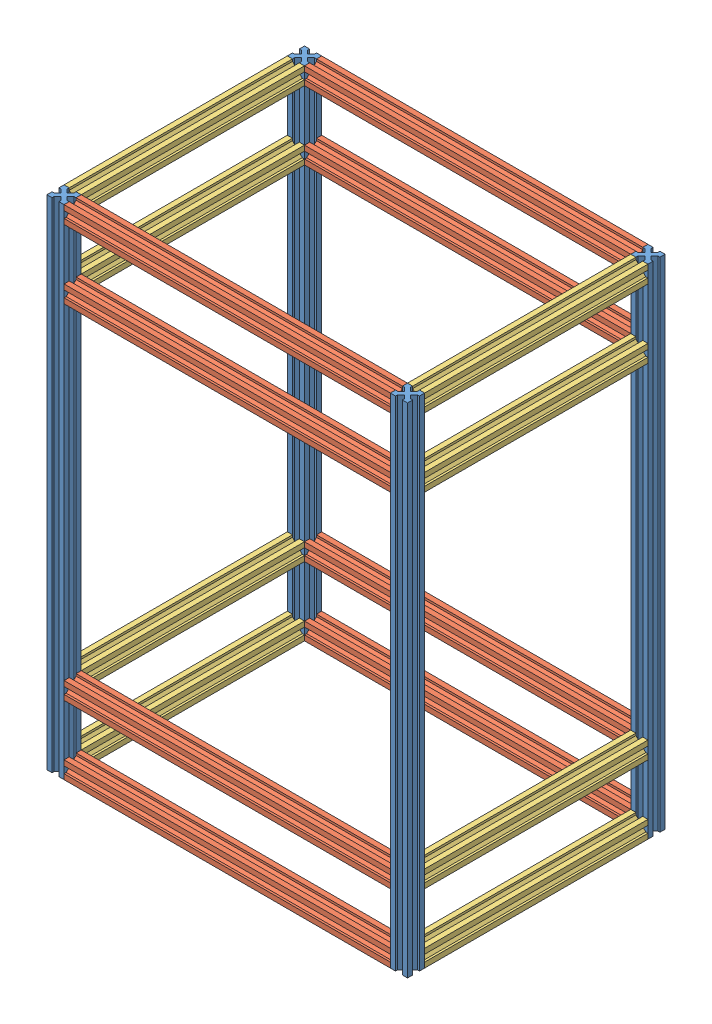
SolidWorks assembly module externe1.0, configuration Défaut. Lengths in mm.
Overall size (420 580 300).
22 component instances, 3 part files, 31 mates.
Components (placement in the parent):
- base chassis horizontale-1: base chassis horizontale [Défaut] at (107.5488 34.6411 0) size (420 580 20)
  - profilé 580-1: profilé 580 [Défaut] at (-152.6624 -292.9685 550) size (20 580 20)
  - profilé 380-1: profilé 380 [Défaut] at (-152.6624 -272.9685 550) x (0 0 1) z (0 1 0) size (20 380 20)
  - profilé 380-2: profilé 380 [Défaut] at (227.3376 -212.9685 550) x (0 0 1) z (0 -1 0) size (20 380 20)
  - profilé 380-3: profilé 380 [Défaut] at (227.3376 267.0315 550) x (0 0 1) z (0 -1 0) size (20 380 20)
  - profilé 380-4: profilé 380 [Défaut] at (227.3376 187.0315 550) x (0 0 1) z (0 -1 0) size (20 380 20)
  - profilé 580-2: profilé 580 [Défaut] at (247.3376 -292.9685 530) x (0 0 -1) z (1 0 0) size (20 580 20)
- profilé 260-1: profilé 260 [Défaut] at (-45.1136 -238.3275 550) x (0 1 0) z (1 0 0) size (20 260 20)
- profilé 260-2: profilé 260 [Défaut] at (334.8864 -258.3275 810) x (-1 0 0) z (0 -1 0) size (20 260 20)
- profilé 260-3: profilé 260 [Défaut] at (334.8864 321.6725 550) x (-1 0 0) z (0 1 0) size (20 260 20)
- profilé 260-4: profilé 260 [Défaut] at (-65.1136 321.6725 550) x (-1 0 0) z (0 1 0) size (20 260 20)
- base chassis horizontale-2: base chassis horizontale [Défaut] at (182.224 28.704 280) x (-1 0 0) z (0 0 1) size (420 580 20)
  - profilé 580-1: profilé 580 [Défaut] at (-152.6624 -292.9685 550) size (20 580 20)
  - profilé 380-1: profilé 380 [Défaut] at (-152.6624 -272.9685 550) x (0 0 1) z (0 1 0) size (20 380 20)
  - profilé 380-2: profilé 380 [Défaut] at (227.3376 -212.9685 550) x (0 0 1) z (0 -1 0) size (20 380 20)
  - profilé 380-3: profilé 380 [Défaut] at (227.3376 267.0315 550) x (0 0 1) z (0 -1 0) size (20 380 20)
  - profilé 380-4: profilé 380 [Défaut] at (227.3376 187.0315 550) x (0 0 1) z (0 -1 0) size (20 380 20)
  - profilé 580-2: profilé 580 [Défaut] at (247.3376 -292.9685 530) x (0 0 -1) z (1 0 0) size (20 580 20)
- profilé 260-5: profilé 260 [Défaut] at (-65.1136 -158.3275 550) x (-1 0 0) z (0 1 0) size (20 260 20)
- profilé 260-6: profilé 260 [Défaut] at (354.8864 -178.3275 550) x (1 0 0) z (0 -1 0) size (20 260 20)
- profilé 260-7: profilé 260 [Défaut] at (334.8864 221.6725 810) x (-1 0 0) z (0 -1 0) size (20 260 20)
- profilé 260-8: profilé 260 [Défaut] at (-45.1136 221.6725 810) x (0 -1 0) z (1 0 0) size (20 260 20)
Mates (geometry in assembly coordinates):
- Coïncidente1: coincident: point of base chassis horizontale-1/profilé 540-1; point of profilé 280-1
- Coïncidente3: coincident: point of base chassis horizontale-1/profilé 380-1; point of profilé 280-1
- Coïncidente4: coincident: point of base chassis horizontale-1/profilé 540-1; point of profilé 280-1
- Coïncidente5: coincident: point of base chassis horizontale-1/profilé 540-2; point of profilé 280-2
- Coïncidente10: coincident: point of base chassis horizontale-1/profilé 540-2; point of profilé 280-2
- Coïncidente11: coincident: line of base chassis horizontale-1/profilé 540-2 through (354.8864 321.6725 550) axis (0 -1 0); point of profilé 280-2
- Coïncidente12: coincident: point of base chassis horizontale-1/profilé 540-2; point of profilé 280-3
- Coïncidente13: coincident: point of base chassis horizontale-1/profilé 380-3; point of profilé 280-3
- Coïncidente14: coincident: line of base chassis horizontale-1/profilé 540-2 through (354.8864 321.6725 550) axis (0 -1 0); point of profilé 280-3
- Coïncidente15: coincident: point of base chassis horizontale-1/profilé 540-1; point of profilé 280-4
- Coïncidente16: coincident: point of base chassis horizontale-1/profilé 380-3; point of profilé 280-4
- Coïncidente17: coincident: line of base chassis horizontale-1/profilé 380-3 through (-45.1136 321.6725 550) axis (1 0 0); point of profilé 280-4
- Coïncidente18: coincident: point of profilé 280-4; point of base chassis horizontale-2/profilé 540-2
- Coïncidente19: coincident: point of profilé 280-4; point of base chassis horizontale-2/profilé 380-1
- Coïncidente20: coincident: point of profilé 280-4; line of base chassis horizontale-2/profilé 540-2 through (-45.1136 -258.3275 810) axis (0 1 0)
- Coïncidente27: coincident: line of base chassis horizontale-1/profilé 540-1 through (-65.1136 321.6725 550) axis (0 -1 0); point of profilé 280-5
- Coïncidente29: coincident: line of base chassis horizontale-1/profilé 540-1 through (-65.1136 321.6725 550) axis (0 -1 0); point of profilé 280-5
- Coïncidente30: coincident: line of base chassis horizontale-1/profilé 540-1 through (-45.1136 321.6725 550) axis (0 -1 0); point of profilé 280-5
- Distance1: distance = 60 mm anti-aligned: plane of profilé 280-1 through (-45.1136 -238.3275 810) normal (0 1 0); plane of profilé 280-5 through (-65.1136 -178.3275 810) normal (0 -1 0)
- Coïncidente32: coincident: line of base chassis horizontale-1/profilé 540-2 through (354.8864 321.6725 550) axis (0 -1 0); point of profilé 280-6
- Coïncidente33: coincident: line of base chassis horizontale-1/profilé 540-2 through (354.8864 321.6725 550) axis (0 -1 0); point of profilé 280-6
- Coïncidente34: coincident: line of base chassis horizontale-1/profilé 540-2 through (334.8864 321.6725 550) axis (0 -1 0); point of profilé 280-6
- Distance2: distance = 60 mm anti-aligned: plane of profilé 280-2 through (334.8864 -238.3275 550) normal (0 1 0); plane of profilé 280-6 through (354.8864 -178.3275 810) normal (0 -1 0)
- Coïncidente36: coincident: line of base chassis horizontale-1/profilé 540-2 through (354.8864 321.6725 550) axis (0 -1 0); point of profilé 280-7
- Coïncidente37: coincident: line of base chassis horizontale-1/profilé 540-2 through (354.8864 321.6725 550) axis (0 -1 0); point of profilé 280-7
- Coïncidente38: coincident: line of base chassis horizontale-1/profilé 540-2 through (334.8864 321.6725 550) axis (0 -1 0); point of profilé 280-7
- Distance3: distance = 60 mm anti-aligned: plane of profilé 280-7 through (334.8864 241.6725 550) normal (0 1 0); plane of profilé 280-3 through (334.8864 301.6725 810) normal (0 -1 0)
- Coïncidente40: coincident: line of base chassis horizontale-2/profilé 540-2 through (-65.1136 -258.3275 810) axis (0 1 0); point of profilé 280-8
- Coïncidente42: coincident: line of base chassis horizontale-2/profilé 540-2 through (-65.1136 -258.3275 810) axis (0 1 0); point of profilé 280-8
- Coïncidente43: coincident: line of base chassis horizontale-2/profilé 540-2 through (-45.1136 -258.3275 810) axis (0 1 0); point of profilé 280-8
- Distance4: distance = 60 mm anti-aligned: plane of profilé 280-4 through (-65.1136 301.6725 810) normal (0 -1 0); plane of profilé 280-8 through (-45.1136 241.6725 550) normal (0 1 0)
